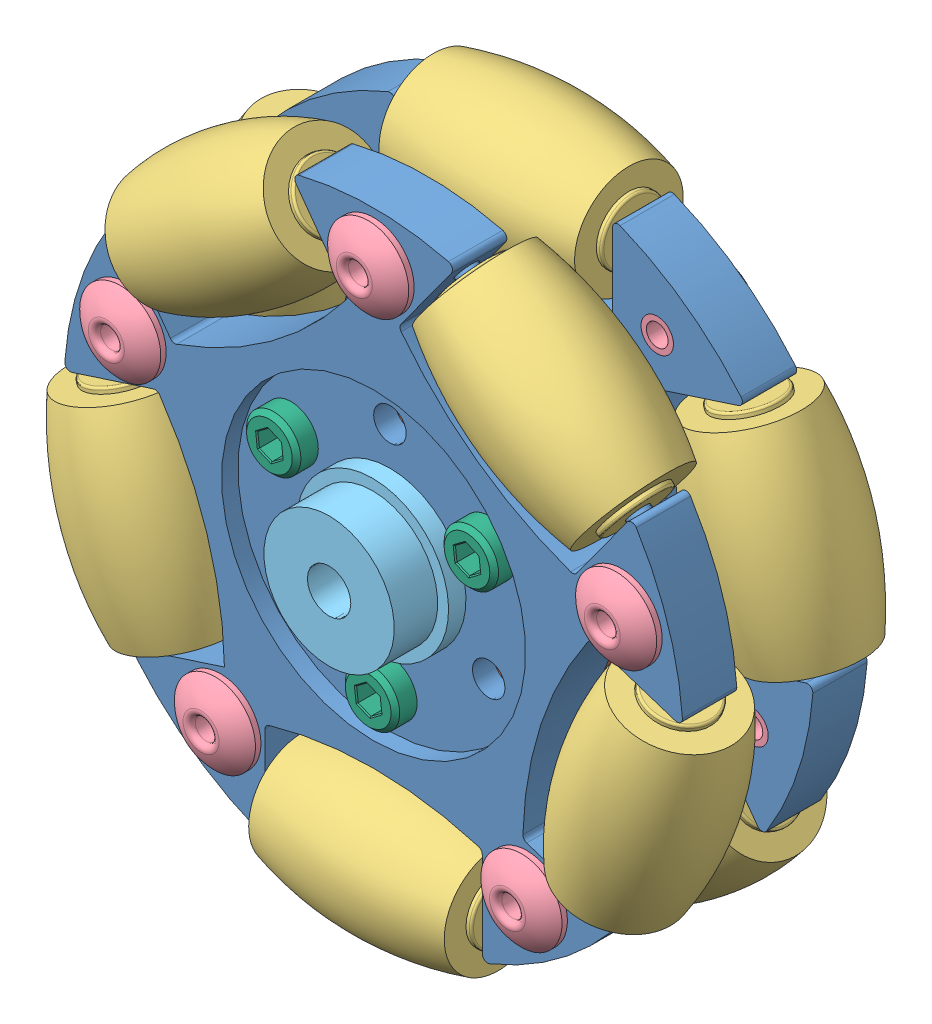
SolidWorks assembly WheelAsm, configuration Default. Lengths in mm.
Overall size (63.86 60.79 27.6).
32 component instances, 8 part files, 20 mates.
Components (placement in the parent):
- WheelBase-2: WheelBase [Default] at (4.9023 2.731 55.3836) x (1 0 0) z (0 -1 0) size (56.86 5 54.96)
- BasePlacer-1: BasePlacer [Default] at (4.9023 2.731 58.8836) x (1 0 0) z (0 -1 0) size (28 10 28)
- RubberWheel-1: RubberWheel [Default] at (4.9023 26.7901 57.8836) x (1 0 0) z (0 -0.999594 -0.028494) size (19 12.5 12.5)
- RubberWheel-2: RubberWheel [Default] at (-17.9792 10.1657 57.8836) x (0.309017 0.951057 0) z (0.95067 -0.308892 -0.028494) size (19 12.5 12.5)
- RubberWheel-3: RubberWheel [Default] at (-9.2392 -16.7332 57.8836) x (-0.809017 0.587785 0) z (0.587547 0.808689 -0.028494) size (19 12.5 12.5)
- RubberWheel-4: RubberWheel [Default] at (19.0439 -16.7332 57.8836) x (-0.809017 -0.587785 0) z (-0.587547 0.808689 -0.028494) size (19 12.5 12.5)
- RubberWheel-5: RubberWheel [Default] at (27.7839 10.1657 57.8836) x (0.309017 -0.951057 0) z (-0.95067 -0.308892 -0.028494) size (19 12.5 12.5)
- Rivet-1: Rivet [Default] at (4.9023 -21.269 54.8836) x (1 0 0) z (0 1 0) size (7.46 6.8 7.46)
- Rivet-2: Rivet [Default] at (27.7277 -4.6854 54.8836) x (0.309017 0.951057 0) z (-0.951057 0.309017 0) size (7.46 6.8 7.46)
- Rivet-3: Rivet [Default] at (19.0092 22.1474 54.8836) x (-0.809017 0.587785 0) z (-0.587785 -0.809017 0) size (7.46 6.8 7.46)
- Rivet-4: Rivet [Default] at (-9.2045 22.1474 54.8836) x (-0.809017 -0.587785 0) z (0.587785 -0.809017 0) size (7.46 6.8 7.46)
- Rivet-5: Rivet [Default] at (-17.923 -4.6854 54.8836) x (0.309017 -0.951057 0) z (0.951057 0.309017 0) size (7.46 6.8 7.46)
- WheelBase-6: WheelBase [Default] at (4.9023 2.731 67.3836) x (-1 0 0) z (0 1 0) size (56.86 5 54.96)
- RubberWheel-16: RubberWheel [Default] at (4.9023 -21.3281 69.8836) size (19 12.5 12.5)
- RubberWheel-17: RubberWheel [Default] at (27.7839 -4.7037 69.8836) x (0.309017 0.951057 0) z (0 0 1) size (19 12.5 12.5)
- RubberWheel-18: RubberWheel [Default] at (19.0439 22.1953 69.8836) x (-0.809017 0.587785 0) z (0 0 1) size (19 12.5 12.5)
- RubberWheel-19: RubberWheel [Default] at (-9.2392 22.1953 69.8836) x (-0.809017 -0.587785 0) z (0 0 1) size (19 12.5 12.5)
- RubberWheel-20: RubberWheel [Default] at (-17.9792 -4.7037 69.8836) x (0.309017 -0.951057 0) z (0 0 1) size (19 12.5 12.5)
- Rivet-16: Rivet [Default] at (-9.2045 -16.6854 72.8836) x (-0.985624 0.168955 0) z (0.168955 0.985624 0) size (7.46 6.8 7.46)
- Rivet-17: Rivet [Default] at (19.0092 -16.6854 72.8836) x (-0.46526 -0.885174 0) z (-0.885174 0.46526 0) size (7.46 6.8 7.46)
- Rivet-18: Rivet [Default] at (27.7277 10.1474 72.8836) x (0.698077 -0.716022 0) z (-0.716022 -0.698077 0) size (7.46 6.8 7.46)
- Rivet-19: Rivet [Default] at (4.9023 26.731 72.8836) x (0.896695 0.442648 0) z (0.442648 -0.896695 0) size (7.46 6.8 7.46)
- Rivet-20: Rivet [Default] at (-17.923 10.1474 72.8836) x (-0.143889 0.989594 0) z (0.989594 0.143889 0) size (7.46 6.8 7.46)
- ShaftConnector-1: ShaftConnector [Default] at (4.9023 2.731 48.8836) x (1 0 0) z (0 -1 0) size (14 27.6 14)
- Part7^WheelAsm-1: Part7^WheelAsm [Default] at origin (virtual)
- Part8^WheelAsm-1: Part8^WheelAsm [Default] at origin (virtual)
- M3HexNut-1: M3HexNut [Default] at (13.9956 7.981 72.8836) x (1 0 0) z (0 0 -1) size (5 5 5)
- M3HexNut-2: M3HexNut [Default] at (-4.1909 7.981 72.8836) x (-0.5 0.866025 0) z (0 0 -1) size (5 5 5)
- M3HexNut-3: M3HexNut [Default] at (4.9023 -7.769 72.8836) x (-0.5 -0.866025 0) z (0 0 -1) size (5 5 5)
- M3HexNut-4: M3HexNut [Default] at (4.9023 -7.769 54.8836) size (5 5 5)
- M3HexNut-5: M3HexNut [Default] at (13.9956 7.981 54.8836) x (-0.5 0.866025 0) z (0 0 1) size (5 5 5)
- M3HexNut-6: M3HexNut [Default] at (-4.1909 7.981 54.8836) x (-0.5 -0.866025 0) z (0 0 1) size (5 5 5)
Mates (geometry in assembly coordinates):
- Concentric2: concentric: cylinder of WheelBase-2 through (4.9023 2.731 55.3836) axis (0 0 1) radius 6; cylinder of BasePlacer-1 through (4.9023 2.731 58.8836) axis (0 0 1) radius 6
- Coincident1: coincident: plane of WheelBase-2 through (4.9023 2.731 58.8836) normal (0 0 1); plane of BasePlacer-1 through (4.9023 2.731 58.8836) normal (0 0 -1)
- Distance1: distance = 1 mm: plane of RubberWheel-1 through (13.9023 26.7901 57.8836) normal (1 0 0); plane of WheelBase-2 through (14.9023 29.419 55.3836) normal (-1 0 0)
- Concentric5: concentric: cylinder of WheelBase-2 through (4.9023 -21.269 55.3836) axis (0 0 1) radius 1.5; cylinder of Rivet-1 through (4.9023 -21.269 60.3836) axis (0 0 -1) radius 1.5
- Coincident6: coincident: plane of WheelBase-2 through (4.9023 2.731 55.3836) normal (0 0 -1); plane of Rivet-1 through (4.9023 -17.5383 55.3836) normal (0 0 1)
- Concentric10: concentric: cylinder of WheelBase-2 through (4.9023 2.731 55.3836) axis (0 0 1) radius 6; cylinder of WheelBase-6 through (4.9023 2.731 67.3836) axis (0 0 1) radius 6
- Coincident10: coincident: plane of BasePlacer-1 through (4.9023 2.731 68.8836) normal (0 0 1); plane of WheelBase-6 through (4.9023 2.731 68.8836) normal (0 0 -1)
- Concentric11: concentric: circle of WheelBase-2; circle of BasePlacer-1
- Coincident13: coincident: cylinder of BasePlacer-1 through (4.9023 13.231 58.8836) axis (0 0 1) radius 1.5; circle of WheelBase-6
- Distance4: distance = 1 mm: plane of RubberWheel-16 through (13.9023 -21.3281 69.8836) normal (1 0 0); plane of WheelBase-6 through (14.9023 -23.957 67.3836) normal (-1 0 0)
- Concentric14: concentric: cylinder of WheelBase-6 through (-9.2045 -16.6854 67.3836) axis (0 0 1) radius 1.5; cylinder of Rivet-16 through (-9.2045 -16.6854 67.3836) axis (0 0 1) radius 1.5
- Coincident17: coincident: plane of WheelBase-6 through (4.9023 2.731 72.3836) normal (0 0 1); plane of Rivet-16 through (-8.5742 -13.0083 72.3836) normal (0 0 -1)
- Concentric15: concentric: cylinder of BasePlacer-1 through (4.9023 2.731 58.8836) axis (0 0 1) radius 6; cylinder of ShaftConnector-1 through (4.9023 2.731 70.8836) axis (0 0 -1) radius 6
- Coincident18: coincident: plane of WheelBase-2 through (4.9023 2.731 56.8836) normal (0 0 -1); plane of ShaftConnector-1 through (4.9023 2.731 56.8836) normal (0 0 1)
- Concentric16: concentric: cylinder of WheelBase-6 through (500004.9023 -21.3281 69.8836) axis (-1 0 0) radius 1; cylinder of RubberWheel-16 through (14.4023 -21.3281 69.8836) axis (-1 0 0) radius 1
- Concentric17: concentric: cylinder of WheelBase-2 through (500004.3146 -363297.8446 57.8836) axis (-0.809017 0.587785 0) radius 1; cylinder of RubberWheel-3 through (-16.9249 -11.1493 57.8836) axis (0.809017 -0.587785 0) radius 1
- Concentric19: concentric: cylinder of WheelBase-6 through (13.9956 7.981 67.3836) axis (0 0 1) radius 1.5; cylinder of M3HexNut-1 through (13.9956 7.981 67.8836) axis (0 0 -1) radius 1.5
- Coincident20: coincident: plane of WheelBase-6 through (4.9023 2.731 70.8836) normal (0 0 1); plane of M3HexNut-1 through (13.9956 5.481 70.8836) normal (0 0 -1)
- Concentric20: concentric: cylinder of WheelBase-2 through (4.9023 -7.769 55.3836) axis (0 0 1) radius 1.5; cylinder of M3HexNut-4 through (4.9023 -7.769 59.8836) axis (0 0 1) radius 1.5
- Coincident21: coincident: plane of WheelBase-2 through (4.9023 2.731 56.8836) normal (0 0 -1); plane of M3HexNut-4 through (4.9023 -5.269 56.8836) normal (0 0 1)
